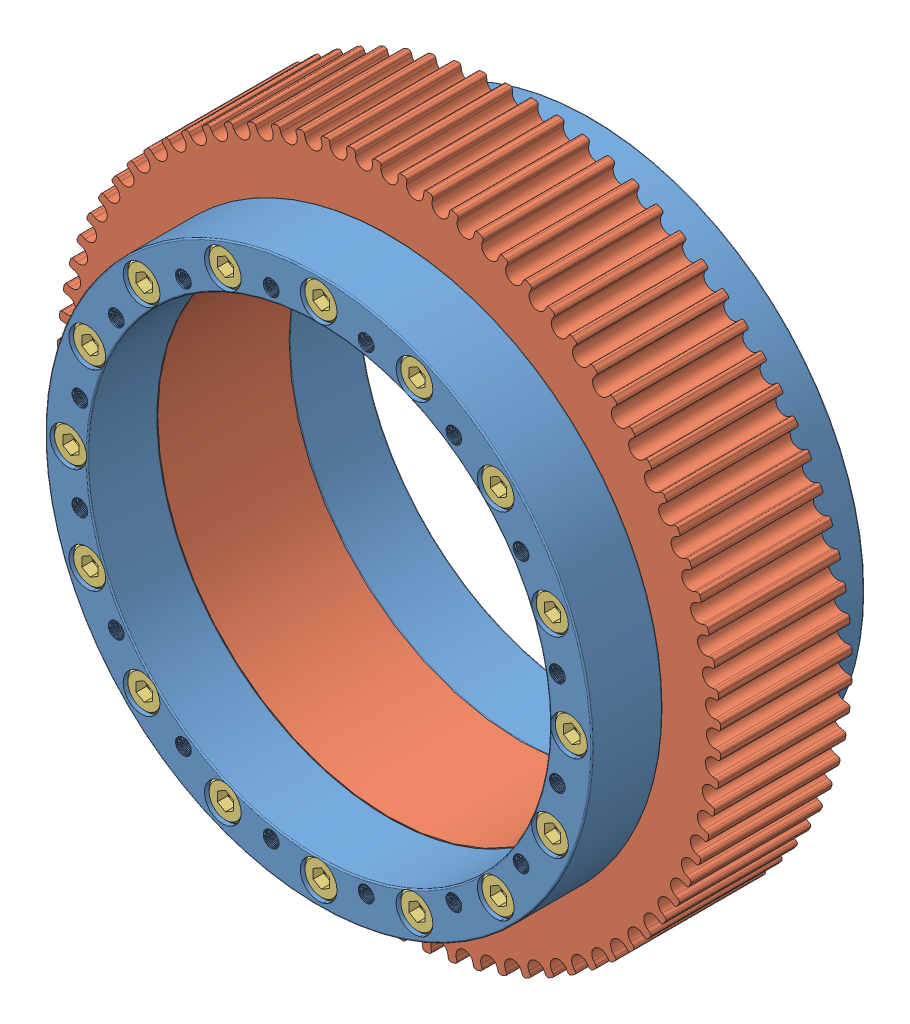
SolidWorks assembly Gear-Bracket-Mesh, configuration Default. Lengths in mm.
Overall size (144.2 144.2 52.22).
35 component instances, 3 part files, 67 mates.
Components (placement in the parent):
- Connecting-Bracket-1: Connecting-Bracket [Default] at (30.3794 121.3729 140.915) size (104 104 13.61)
- Final-Gear-Drive-80T-1: Final-Gear-Drive-80T [Default] at (30.3049 121.3421 121.69) x (0.999999 -0.001693 0) z (0 0 1) size (126.11 126.11 25.11)
- Connecting-Bracket-3: Connecting-Bracket [Default] at (30.3049 121.3421 102.465) x (0.832409 0.554162 0) z (0 0 -1) size (104 104 13.61)
- socket head cap screw_am-61: socket head cap screw_am [B18.3.1M - 4 x 0.7 x 16 Hex SHCS -- 16NHX] at (48.6066 165.3772 147.14) x (0 0 -1) z (1 0 0) size (20 7 7)
- socket head cap screw_am-62: socket head cap screw_am [B18.3.1M - 4 x 0.7 x 16 Hex SHCS -- 16NHX] at (64.0589 155.0524 147.14) x (0 0 -1) z (1 0 0) size (20 7 7)
- socket head cap screw_am-63: socket head cap screw_am [B18.3.1M - 4 x 0.7 x 16 Hex SHCS -- 16NHX] at (74.3838 139.6001 147.14) x (0 0 -1) z (1 0 0) size (20 7 7)
- socket head cap screw_am-64: socket head cap screw_am [B18.3.1M - 4 x 0.7 x 16 Hex SHCS -- 16NHX] at (78.0094 121.3729 147.14) x (0 0 -1) z (1 0 0) size (20 7 7)
- socket head cap screw_am-65: socket head cap screw_am [B18.3.1M - 4 x 0.7 x 16 Hex SHCS -- 16NHX] at (74.3838 103.1456 147.14) x (0 0 -1) z (1 0 0) size (20 7 7)
- socket head cap screw_am-66: socket head cap screw_am [B18.3.1M - 4 x 0.7 x 16 Hex SHCS -- 16NHX] at (-13.625 103.1456 147.14) x (0 0 -1) z (1 0 0) size (20 7 7)
- socket head cap screw_am-67: socket head cap screw_am [B18.3.1M - 4 x 0.7 x 16 Hex SHCS -- 16NHX] at (-17.2506 121.3729 147.14) x (0 0 -1) z (1 0 0) size (20 7 7)
- socket head cap screw_am-68: socket head cap screw_am [B18.3.1M - 4 x 0.7 x 16 Hex SHCS -- 16NHX] at (-13.625 139.6001 147.14) x (0 0 -1) z (1 0 0) size (20 7 7)
- socket head cap screw_am-69: socket head cap screw_am [B18.3.1M - 4 x 0.7 x 16 Hex SHCS -- 16NHX] at (-3.3001 155.0524 147.14) x (0 0 -1) z (1 0 0) size (20 7 7)
- socket head cap screw_am-70: socket head cap screw_am [B18.3.1M - 4 x 0.7 x 16 Hex SHCS -- 16NHX] at (12.1522 165.3772 147.14) x (0 0 -1) z (1 0 0) size (20 7 7)
- socket head cap screw_am-71: socket head cap screw_am [B18.3.1M - 4 x 0.7 x 16 Hex SHCS -- 16NHX] at (30.3794 169.0029 147.14) x (0 0 -1) z (1 0 0) size (20 7 7)
- socket head cap screw_am-72: socket head cap screw_am [B18.3.1M - 4 x 0.7 x 16 Hex SHCS -- 16NHX] at (-3.3001 87.6934 147.14) x (0 0 -1) z (1 0 0) size (20 7 7)
- socket head cap screw_am-73: socket head cap screw_am [B18.3.1M - 4 x 0.7 x 16 Hex SHCS -- 16NHX] at (12.1522 77.3685 147.14) x (0 0 -1) z (1 0 0) size (20 7 7)
- socket head cap screw_am-74: socket head cap screw_am [B18.3.1M - 4 x 0.7 x 16 Hex SHCS -- 16NHX] at (30.3794 73.7429 147.14) x (0 0 -1) z (1 0 0) size (20 7 7)
- socket head cap screw_am-75: socket head cap screw_am [B18.3.1M - 4 x 0.7 x 16 Hex SHCS -- 16NHX] at (48.6066 77.3685 147.14) x (0 0 -1) z (1 0 0) size (20 7 7)
- socket head cap screw_am-76: socket head cap screw_am [B18.3.1M - 4 x 0.7 x 16 Hex SHCS -- 16NHX] at (64.0589 87.6934 147.14) x (0 0 -1) z (1 0 0) size (20 7 7)
- socket head cap screw_am-77: socket head cap screw_am [B18.3.1M - 4 x 0.7 x 16 Hex SHCS -- 16NHX] at (3.9102 160.9897 96.24) x (0 0 1) z (-1 0 0) size (20 7 7)
- socket head cap screw_am-79: socket head cap screw_am [B18.3.1M - 4 x 0.7 x 16 Hex SHCS -- 16NHX] at (-9.2531 147.8709 96.24) x (0 0 1) z (-1 0 0) size (20 7 7)
- socket head cap screw_am-80: socket head cap screw_am [B18.3.1M - 4 x 0.7 x 16 Hex SHCS -- 16NHX] at (-16.3941 130.7133 96.24) x (0 0 1) z (-1 0 0) size (20 7 7)
- socket head cap screw_am-82: socket head cap screw_am [B18.3.1M - 4 x 0.7 x 16 Hex SHCS -- 16NHX] at (-9.3427 94.9473 96.24) x (0 0 1) z (-1 0 0) size (20 7 7)
- socket head cap screw_am-83: socket head cap screw_am [B18.3.1M - 4 x 0.7 x 16 Hex SHCS -- 16NHX] at (3.7761 81.784 96.24) x (0 0 1) z (-1 0 0) size (20 7 7)
- socket head cap screw_am-84: socket head cap screw_am [B18.3.1M - 4 x 0.7 x 16 Hex SHCS -- 16NHX] at (20.9337 74.6431 96.24) x (0 0 1) z (-1 0 0) size (20 7 7)
- socket head cap screw_am-85: socket head cap screw_am [B18.3.1M - 4 x 0.7 x 16 Hex SHCS -- 16NHX] at (39.6761 168.0411 96.24) x (0 0 1) z (-1 0 0) size (20 7 7)
- socket head cap screw_am-86: socket head cap screw_am [B18.3.1M - 4 x 0.7 x 16 Hex SHCS -- 16NHX] at (21.0918 168.0725 96.24) x (0 0 1) z (-1 0 0) size (20 7 7)
- socket head cap screw_am-88: socket head cap screw_am [B18.3.1M - 4 x 0.7 x 16 Hex SHCS -- 16NHX] at (56.8337 160.9001 96.24) x (0 0 1) z (-1 0 0) size (20 7 7)
- socket head cap screw_am-89: socket head cap screw_am [B18.3.1M - 4 x 0.7 x 16 Hex SHCS -- 16NHX] at (69.9525 147.7368 96.24) x (0 0 1) z (-1 0 0) size (20 7 7)
- socket head cap screw_am-91: socket head cap screw_am [B18.3.1M - 4 x 0.7 x 16 Hex SHCS -- 16NHX] at (56.6997 81.6944 96.24) x (0 0 1) z (-1 0 0) size (20 7 7)
- socket head cap screw_am-92: socket head cap screw_am [B18.3.1M - 4 x 0.7 x 16 Hex SHCS -- 16NHX] at (39.518 74.6116 96.24) x (0 0 1) z (-1 0 0) size (20 7 7)
- socket head cap screw_am-94: socket head cap screw_am [B18.3.1M - 4 x 0.7 x 16 Hex SHCS -- 16NHX] at (69.863 94.8133 96.24) x (0 0 1) z (-1 0 0) size (20 7 7)
- socket head cap screw_am-96: socket head cap screw_am [B18.3.1M - 4 x 0.7 x 16 Hex SHCS -- 16NHX] at (77.0039 111.9709 96.24) x (0 0 1) z (-1 0 0) size (20 7 7)
- socket head cap screw_am-97: socket head cap screw_am [B18.3.1M - 4 x 0.7 x 16 Hex SHCS -- 16NHX] at (77.0354 130.5551 96.24) x (0 0 1) z (-1 0 0) size (20 7 7)
- socket head cap screw_am-99: socket head cap screw_am [B18.3.1M - 4 x 0.7 x 16 Hex SHCS -- 16NHX] at (-16.4256 112.129 96.24) x (0 0 1) z (-1 0 0) size (20 7 7)
Mates (geometry in assembly coordinates):
- Lock3: lock: unknown of Connecting-Bracket-1; unknown of Final-Gear-Drive-80T-1
- Coincident74: coincident aligned: circle of Final-Gear-Drive-80T-1; circle of Connecting-Bracket-3
- Lock5: lock: unknown of Final-Gear-Drive-80T-1; unknown of Connecting-Bracket-3
- Concentric56: concentric aligned: cylinder of Connecting-Bracket-1 through (48.6066 165.3772 134.19) axis (0 0 1) radius 2; cylinder of socket head cap screw_am-61 through (48.6066 165.3772 178.89) axis (0 0 1) radius 3.5
- Coincident77: coincident anti-aligned: plane of Connecting-Bracket-1 through (48.6066 165.3772 143.14) normal (0 0 1); plane of socket head cap screw_am-61 through (48.6066 168.8772 143.14) normal (0 0 -1)
- Concentric57: concentric aligned: cylinder of Connecting-Bracket-1 through (64.0589 155.0524 134.19) axis (0 0 1) radius 2; cylinder of socket head cap screw_am-62 through (64.0589 155.0524 178.89) axis (0 0 1) radius 3.5
- Coincident78: coincident anti-aligned: plane of Connecting-Bracket-1 through (64.0589 155.0524 143.14) normal (0 0 1); plane of socket head cap screw_am-62 through (64.0589 158.5524 143.14) normal (0 0 -1)
- Concentric58: concentric aligned: cylinder of Connecting-Bracket-1 through (74.3838 139.6001 143.14) axis (0 0 1) radius 3.5; cylinder of socket head cap screw_am-63 through (74.3838 139.6001 178.89) axis (0 0 1) radius 3.5
- Coincident79: coincident anti-aligned: plane of Connecting-Bracket-1 through (74.3838 139.6001 143.14) normal (0 0 1); plane of socket head cap screw_am-63 through (74.3838 143.1001 143.14) normal (0 0 -1)
- Concentric59: concentric aligned: cylinder of Connecting-Bracket-1 through (78.0094 121.3729 134.19) axis (0 0 1) radius 2; cylinder of socket head cap screw_am-64 through (78.0094 121.3729 178.89) axis (0 0 1) radius 3.5
- Coincident80: coincident anti-aligned: plane of Connecting-Bracket-1 through (78.0094 121.3729 143.14) normal (0 0 1); plane of socket head cap screw_am-64 through (78.0094 124.8729 143.14) normal (0 0 -1)
- Concentric60: concentric aligned: cylinder of Connecting-Bracket-1 through (74.3838 103.1456 134.19) axis (0 0 1) radius 2; cylinder of socket head cap screw_am-65 through (74.3838 103.1456 178.89) axis (0 0 1) radius 3.5
- Coincident81: coincident anti-aligned: plane of Connecting-Bracket-1 through (74.3838 103.1456 143.14) normal (0 0 1); plane of socket head cap screw_am-65 through (74.3838 106.6456 143.14) normal (0 0 -1)
- Concentric61: concentric aligned: cylinder of Connecting-Bracket-1 through (-13.625 103.1456 134.19) axis (0 0 1) radius 2; cylinder of socket head cap screw_am-66 through (-13.625 103.1456 178.89) axis (0 0 1) radius 3.5
- Coincident82: coincident anti-aligned: plane of Connecting-Bracket-1 through (-13.625 103.1456 143.14) normal (0 0 1); plane of socket head cap screw_am-66 through (-13.625 106.6456 143.14) normal (0 0 -1)
- Concentric62: concentric aligned: cylinder of Connecting-Bracket-1 through (-17.2506 121.3729 134.19) axis (0 0 1) radius 2; cylinder of socket head cap screw_am-67 through (-17.2506 121.3729 178.89) axis (0 0 1) radius 3.5
- Coincident83: coincident anti-aligned: plane of Connecting-Bracket-1 through (-17.2506 121.3729 143.14) normal (0 0 1); plane of socket head cap screw_am-67 through (-17.2506 124.8729 143.14) normal (0 0 -1)
- Concentric63: concentric aligned: cylinder of Connecting-Bracket-1 through (-13.625 139.6001 134.19) axis (0 0 1) radius 2; cylinder of socket head cap screw_am-68 through (-13.625 139.6001 178.89) axis (0 0 1) radius 3.5
- Coincident84: coincident anti-aligned: plane of Connecting-Bracket-1 through (-13.625 139.6001 143.14) normal (0 0 1); plane of socket head cap screw_am-68 through (-13.625 143.1001 143.14) normal (0 0 -1)
- Concentric64: concentric aligned: cylinder of Connecting-Bracket-1 through (-3.3001 155.0524 134.19) axis (0 0 1) radius 2; cylinder of socket head cap screw_am-69 through (-3.3001 155.0524 178.89) axis (0 0 1) radius 3.5
- Coincident85: coincident anti-aligned: plane of Connecting-Bracket-1 through (-3.3001 155.0524 143.14) normal (0 0 1); plane of socket head cap screw_am-69 through (-3.3001 158.5524 143.14) normal (0 0 -1)
- Concentric65: concentric aligned: cylinder of Connecting-Bracket-1 through (12.1522 165.3772 134.19) axis (0 0 1) radius 2; cylinder of socket head cap screw_am-70 through (12.1522 165.3772 178.89) axis (0 0 1) radius 3.5
- Coincident86: coincident anti-aligned: plane of Connecting-Bracket-1 through (12.1522 165.3772 143.14) normal (0 0 1); plane of socket head cap screw_am-70 through (12.1522 168.8772 143.14) normal (0 0 -1)
- Concentric66: concentric aligned: cylinder of Connecting-Bracket-1 through (30.3794 169.0029 134.19) axis (0 0 1) radius 2; cylinder of socket head cap screw_am-71 through (30.3794 169.0029 178.89) axis (0 0 1) radius 3.5
- Coincident87: coincident anti-aligned: plane of Connecting-Bracket-1 through (30.3794 169.0029 143.14) normal (0 0 1); plane of socket head cap screw_am-71 through (30.3794 172.5029 143.14) normal (0 0 -1)
- Concentric67: concentric aligned: cylinder of Connecting-Bracket-1 through (-3.3001 87.6934 134.19) axis (0 0 1) radius 2; cylinder of socket head cap screw_am-72 through (-3.3001 87.6934 178.89) axis (0 0 1) radius 3.5
- Coincident88: coincident anti-aligned: plane of Connecting-Bracket-1 through (-3.3001 87.6934 143.14) normal (0 0 1); plane of socket head cap screw_am-72 through (-3.3001 91.1934 143.14) normal (0 0 -1)
- Concentric68: concentric aligned: cylinder of Connecting-Bracket-1 through (12.1522 77.3685 134.19) axis (0 0 1) radius 2; cylinder of socket head cap screw_am-73 through (12.1522 77.3685 178.89) axis (0 0 1) radius 3.5
- Coincident89: coincident anti-aligned: plane of Connecting-Bracket-1 through (12.1522 77.3685 143.14) normal (0 0 1); plane of socket head cap screw_am-73 through (12.1522 80.8685 143.14) normal (0 0 -1)
- Concentric69: concentric aligned: cylinder of Connecting-Bracket-1 through (30.3794 73.7429 134.19) axis (0 0 1) radius 2; cylinder of socket head cap screw_am-74 through (30.3794 73.7429 178.89) axis (0 0 1) radius 3.5
- Coincident90: coincident anti-aligned: plane of Connecting-Bracket-1 through (30.3794 73.7429 143.14) normal (0 0 1); plane of socket head cap screw_am-74 through (30.3794 77.2429 143.14) normal (0 0 -1)
- Concentric70: concentric aligned: cylinder of Connecting-Bracket-1 through (48.6066 77.3685 143.14) axis (0 0 1) radius 3.5; cylinder of socket head cap screw_am-75 through (48.6066 77.3685 178.89) axis (0 0 1) radius 3.5
- Coincident91: coincident anti-aligned: plane of Connecting-Bracket-1 through (48.6066 77.3685 143.14) normal (0 0 1); plane of socket head cap screw_am-75 through (48.6066 80.8685 143.14) normal (0 0 -1)
- Concentric71: concentric aligned: cylinder of Connecting-Bracket-1 through (64.0589 87.6934 134.19) axis (0 0 1) radius 2; cylinder of socket head cap screw_am-76 through (64.0589 87.6934 178.89) axis (0 0 1) radius 3.5
- Coincident92: coincident anti-aligned: plane of Connecting-Bracket-1 through (64.0589 87.6934 143.14) normal (0 0 1); plane of socket head cap screw_am-76 through (64.0589 91.1934 143.14) normal (0 0 -1)
- Concentric72: concentric aligned: cylinder of Connecting-Bracket-3 through (3.9102 160.9897 109.19) axis (0 0 -1) radius 2; cylinder of socket head cap screw_am-77 through (3.9102 160.9897 64.49) axis (0 0 -1) radius 3.5
- Coincident93: coincident anti-aligned: plane of Connecting-Bracket-3 through (3.9102 160.9897 100.24) normal (0 0 -1); plane of socket head cap screw_am-77 through (3.9102 164.4897 100.24) normal (0 0 1)
- Concentric73: concentric aligned: cylinder of Connecting-Bracket-3 through (-9.2531 147.8709 109.19) axis (0 0 -1) radius 2; cylinder of socket head cap screw_am-79 through (-9.2531 147.8709 64.49) axis (0 0 -1) radius 3.5
- Coincident94: coincident anti-aligned: plane of Connecting-Bracket-3 through (-9.2531 147.8709 100.24) normal (0 0 -1); plane of socket head cap screw_am-79 through (-9.2531 151.3709 100.24) normal (0 0 1)
- Concentric74: concentric aligned: cylinder of Connecting-Bracket-3 through (-16.3941 130.7133 100.24) axis (0 0 -1) radius 3.5; cylinder of socket head cap screw_am-80 through (-16.3941 130.7133 64.49) axis (0 0 -1) radius 3.5
- Coincident95: coincident anti-aligned: plane of Connecting-Bracket-3 through (-16.3941 130.7133 100.24) normal (0 0 -1); plane of socket head cap screw_am-80 through (-16.3941 134.2133 100.24) normal (0 0 1)
- Concentric75: concentric aligned: cylinder of Connecting-Bracket-3 through (-9.3427 94.9473 109.19) axis (0 0 -1) radius 2; cylinder of socket head cap screw_am-82 through (-9.3427 94.9473 64.49) axis (0 0 -1) radius 3.5
- Coincident96: coincident anti-aligned: plane of Connecting-Bracket-3 through (-9.3427 94.9473 100.24) normal (0 0 -1); plane of socket head cap screw_am-82 through (-9.3427 98.4473 100.24) normal (0 0 1)
- Concentric76: concentric aligned: cylinder of Connecting-Bracket-3 through (3.7761 81.784 109.19) axis (0 0 -1) radius 2; cylinder of socket head cap screw_am-83 through (3.7761 81.784 64.49) axis (0 0 -1) radius 3.5
- Coincident97: coincident anti-aligned: plane of Connecting-Bracket-3 through (3.7761 81.784 100.24) normal (0 0 -1); plane of socket head cap screw_am-83 through (3.7761 85.284 100.24) normal (0 0 1)
- Concentric77: concentric aligned: cylinder of Connecting-Bracket-3 through (20.9337 74.6431 109.19) axis (0 0 -1) radius 2; cylinder of socket head cap screw_am-84 through (20.9337 74.6431 64.49) axis (0 0 -1) radius 3.5
- Coincident98: coincident anti-aligned: plane of Connecting-Bracket-3 through (20.9337 74.6431 100.24) normal (0 0 -1); plane of socket head cap screw_am-84 through (20.9337 78.1431 100.24) normal (0 0 1)
- Concentric78: concentric aligned: cylinder of Connecting-Bracket-3 through (39.6761 168.0411 109.19) axis (0 0 -1) radius 2; cylinder of socket head cap screw_am-85 through (39.6761 168.0411 64.49) axis (0 0 -1) radius 3.5
- Coincident99: coincident anti-aligned: plane of Connecting-Bracket-3 through (39.6761 168.0411 100.24) normal (0 0 -1); plane of socket head cap screw_am-85 through (39.6761 171.5411 100.24) normal (0 0 1)
- Concentric79: concentric aligned: cylinder of Connecting-Bracket-3 through (21.0918 168.0725 109.19) axis (0 0 -1) radius 2; cylinder of socket head cap screw_am-86 through (21.0918 168.0725 64.49) axis (0 0 -1) radius 3.5
- Coincident100: coincident anti-aligned: plane of Connecting-Bracket-3 through (21.0918 168.0725 100.24) normal (0 0 -1); plane of socket head cap screw_am-86 through (21.0918 171.5725 100.24) normal (0 0 1)
- Concentric80: concentric aligned: cylinder of Connecting-Bracket-3 through (56.8337 160.9001 100.24) axis (0 0 -1) radius 3.5; cylinder of socket head cap screw_am-88 through (56.8337 160.9001 64.49) axis (0 0 -1) radius 3.5
- Coincident101: coincident anti-aligned: plane of Connecting-Bracket-3 through (56.8337 160.9001 100.24) normal (0 0 -1); plane of socket head cap screw_am-88 through (56.8337 164.4001 100.24) normal (0 0 1)
- Concentric81: concentric aligned: cylinder of Connecting-Bracket-3 through (69.9525 147.7368 100.24) axis (0 0 -1) radius 3.5; cylinder of socket head cap screw_am-89 through (69.9525 147.7368 64.49) axis (0 0 -1) radius 3.5
- Coincident102: coincident anti-aligned: plane of Connecting-Bracket-3 through (69.9525 147.7368 100.24) normal (0 0 -1); plane of socket head cap screw_am-89 through (69.9525 151.2368 100.24) normal (0 0 1)
- Concentric82: concentric aligned: cylinder of Connecting-Bracket-3 through (56.6997 81.6944 109.19) axis (0 0 -1) radius 2; cylinder of socket head cap screw_am-91 through (56.6997 81.6944 64.49) axis (0 0 -1) radius 3.5
- Coincident103: coincident anti-aligned: plane of Connecting-Bracket-3 through (56.6997 81.6944 100.24) normal (0 0 -1); plane of socket head cap screw_am-91 through (56.6997 85.1944 100.24) normal (0 0 1)
- Concentric83: concentric aligned: cylinder of Connecting-Bracket-3 through (39.518 74.6116 100.24) axis (0 0 -1) radius 3.5; cylinder of socket head cap screw_am-92 through (39.518 74.6116 64.49) axis (0 0 -1) radius 3.5
- Coincident104: coincident anti-aligned: plane of Connecting-Bracket-3 through (39.518 74.6116 100.24) normal (0 0 -1); plane of socket head cap screw_am-92 through (39.518 78.1116 100.24) normal (0 0 1)
- Concentric84: concentric aligned: cylinder of Connecting-Bracket-3 through (69.863 94.8133 109.19) axis (0 0 -1) radius 2; cylinder of socket head cap screw_am-94 through (69.863 94.8133 64.49) axis (0 0 -1) radius 3.5
- Coincident105: coincident anti-aligned: plane of Connecting-Bracket-3 through (69.863 94.8133 100.24) normal (0 0 -1); plane of socket head cap screw_am-94 through (69.863 98.3133 100.24) normal (0 0 1)
- Concentric85: concentric aligned: cylinder of Connecting-Bracket-3 through (77.0039 111.9709 100.24) axis (0 0 -1) radius 3.5; cylinder of socket head cap screw_am-96 through (77.0039 111.9709 64.49) axis (0 0 -1) radius 3.5
- Coincident106: coincident anti-aligned: plane of Connecting-Bracket-3 through (77.0039 111.9709 100.24) normal (0 0 -1); plane of socket head cap screw_am-96 through (77.0039 115.4709 100.24) normal (0 0 1)
- Concentric86: concentric aligned: cylinder of Connecting-Bracket-3 through (77.0354 130.5551 100.24) axis (0 0 -1) radius 3.5; cylinder of socket head cap screw_am-97 through (77.0354 130.5551 64.49) axis (0 0 -1) radius 3.5
- Coincident107: coincident anti-aligned: plane of Connecting-Bracket-3 through (77.0354 130.5551 100.24) normal (0 0 -1); plane of socket head cap screw_am-97 through (77.0354 134.0551 100.24) normal (0 0 1)
- Concentric87: concentric aligned: cylinder of Connecting-Bracket-3 through (-16.4256 112.129 109.19) axis (0 0 -1) radius 2; cylinder of socket head cap screw_am-99 through (-16.4256 112.129 64.49) axis (0 0 -1) radius 3.5
- Coincident108: coincident anti-aligned: plane of Connecting-Bracket-3 through (-16.4256 112.129 100.24) normal (0 0 -1); plane of socket head cap screw_am-99 through (-16.4256 115.629 100.24) normal (0 0 1)
